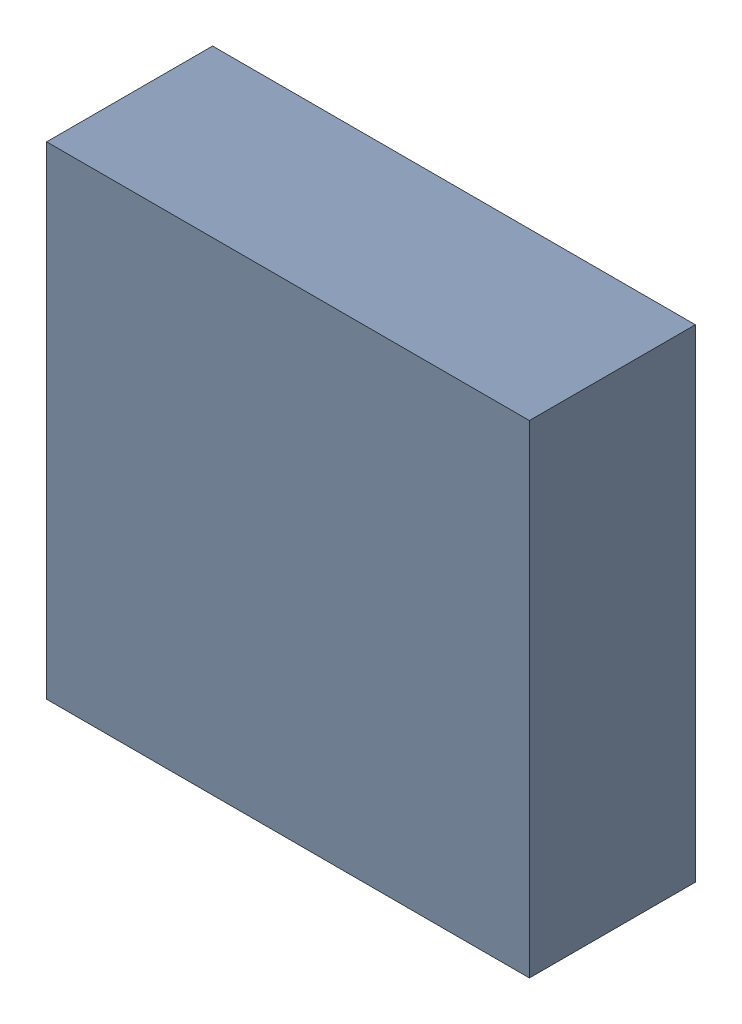
SolidWorks assembly U305_2PCB, configuration Default. Lengths in mm.
Overall size (3.2 3.2 1.1).
2 component instances, 1 part files, 0 mates.
Components (placement in the parent):
- 846484240-1: 846484240 [Default] at (129.8 95.6 -2.7638) size (3.2 3.2 1.1)
  - Extruded_11-1: Extruded_11 [Default] at origin size (3.2 3.2 1.1)
